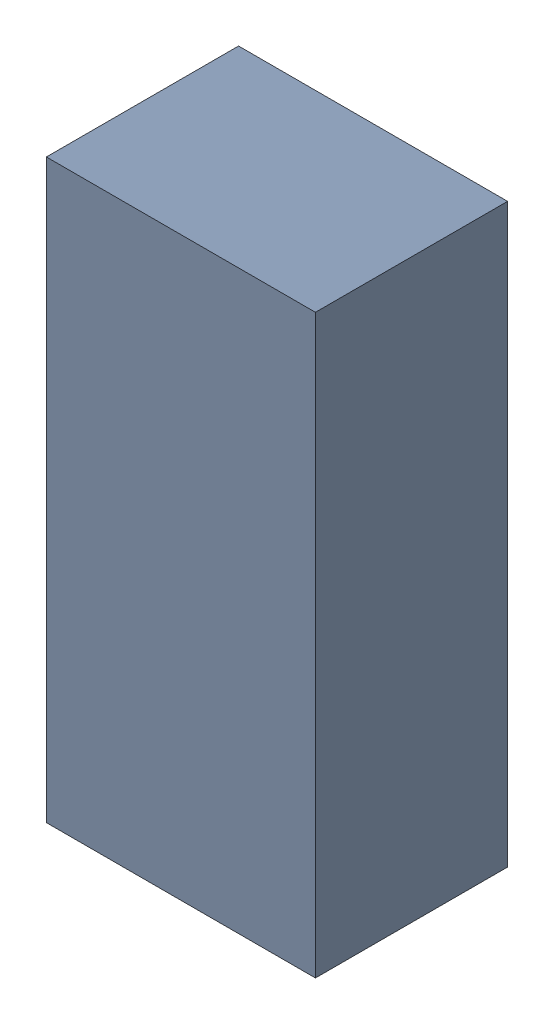
SolidWorks assembly Q3-1, configuration Default. Lengths in mm.
Overall size (1.4 3 1).
2 component instances, 1 part files, 0 mates.
Components (placement in the parent):
- 959206624-1-1: 959206624-1 [Default] at (105.664 90.805 0.1) size (1.4 3 1)
  - Extruded-41-1: Extruded-41 [Default] at origin size (1.4 3 1)
